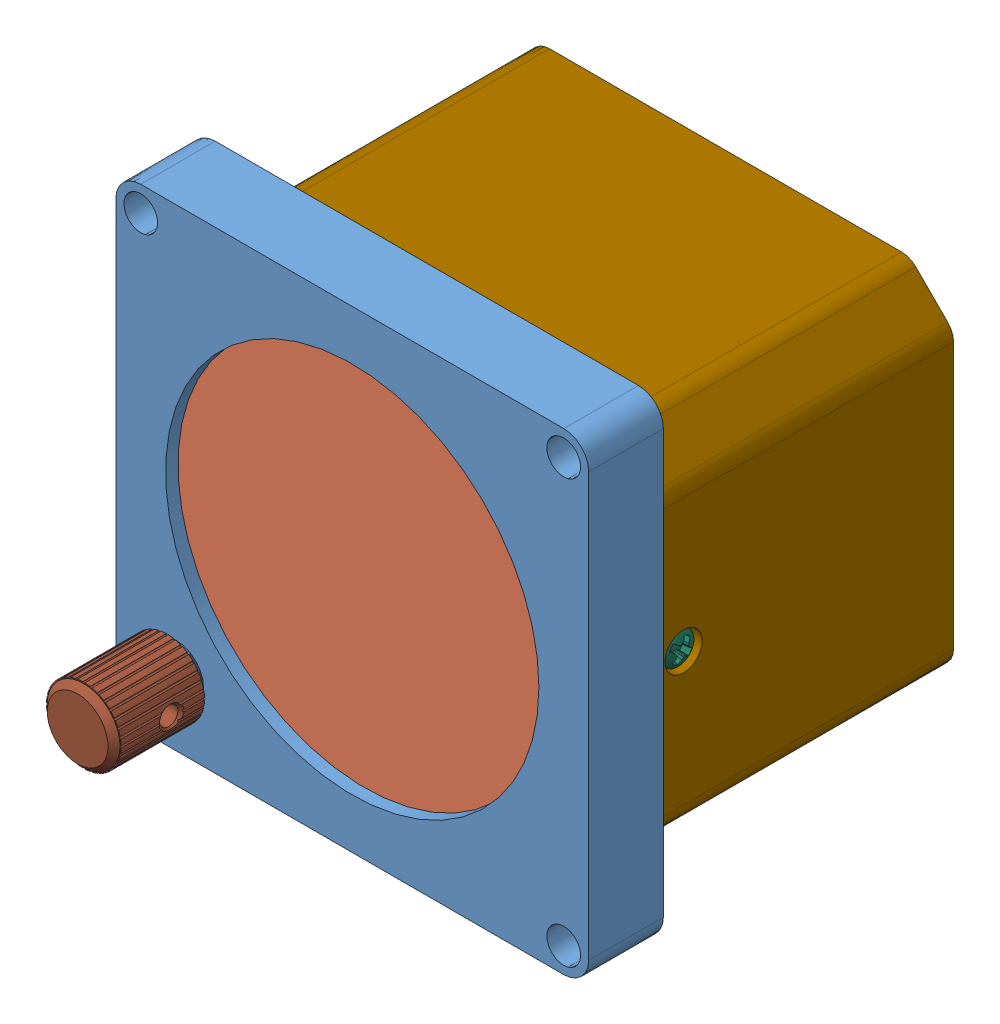
SolidWorks assembly Altimeter, configuration Default. Lengths in mm.
Overall size (60.32 60.32 60.2).
41 component instances, 17 part files, 100 mates.
Components (placement in the parent):
- Altimeter Bezel-1: Altimeter Bezel [Default] at origin size (60.32 60.32 9.53)
- Airspeed Indicator Cover Glass-1: Airspeed Indicator Cover Glass [Default] at (0 0 6.35) size (49.91 49.91 1.59)
- Airspeed Indicator Dial Face Spacer-1: Airspeed Indicator Dial Face Spacer [Default] at (0 0 1.5875) size (49.91 49.91 4.76)
- Altimeter Dial Face-1: Altimeter Dial Face [Default] at origin size (47.65 47.65 1.59)
- Altimeter Stepper Mount-1: Altimeter Stepper Mount [Default] x (-1 0 0) z (0 0 -1) size (56.37 49.44 7.31)
- Altimeter Indicator Pointer-1: Altimeter Indicator Pointer [Default] at (0 0 3.175) x (-0.470884 0.882195 0) z (0 0 1) size (3.17 35.56 0.76)
- DFR0376 DISPLAY-1: DFR0376 DISPLAY [Default] at (72.1555 -12.024 0.081) size (15.3 10.2 0.93)
- DFR0376 PCB-2: DFR0376 PCB [Default] at (-26.7105 60.1578 -5.08) x (0 1 0) z (0 0 1) size (17.8 15.5 2.87)
- DFR0376 DISPLAY-2: DFR0376 DISPLAY [Default] at (-81.2551 4.6281 0.081) x (-1 0 0) z (0 0 1) size (15.3 10.2 0.93)
- DFR0376 PCB-3: DFR0376 PCB [Default] at (19.5694 -79.5565 -5.08) x (0 -1 0) z (0 0 1) size (17.8 15.5 2.87)
- Altimeter Case-1: Altimeter Case [Default] x (-1 0 0) z (0 0 -1) size (59.24 53.76 38.1)
- PEC11R-4230F-N0024-1: PEC11R-4230F-N0024 [Default] at (-22.456 -21.4503 -10.95) x (0 1 0) z (1 0 0) size (12.5 40.2 13.9)
- Altimeter Knob-1: Altimeter Knob [Default] at (-22.456 -21.4503 9.398) x (0 -1 0) z (-1 0 0) size (9.52 11.43 9.53)
- VID29-02-1: VID29-02 [Default] at (1.5529 5.7956 -14.013) x (0.965926 -0.258819 0) z (-0.258819 -0.965926 0) size (31.7 22.35 29.3)
- MD-80PL100-1: MD-80PL100 [Default] at (0 13.4938 -34.29) x (0 0 -1) z (1 0 0) size (21.05 14 25)
- MD-80PL100-2: MD-80PL100 [Default] at (0 -2.3813 -34.29) x (0 0 -1) z (1 0 0) size (21.05 14 25)
- MD-80PL100-3: MD-80PL100 [Default] at (0 -18.2563 -34.29) x (0 0 -1) z (1 0 0) size (21.05 14 25)
- 93365A110_BRASS HEAT-SET INSERT FOR PLASTICS_2-56-2: 93365A110_BRASS HEAT-SET INSERT FOR PLASTICS_2-56 [Default] at (-27.2185 10.9575 -3.6565) x (0 0.185827 0.982583) z (0 -0.982583 0.185827) size (3.58 3.09 3.58)
- 93365A110_BRASS HEAT-SET INSERT FOR PLASTICS_2-56-6: 93365A110_BRASS HEAT-SET INSERT FOR PLASTICS_2-56 [Default] at (0 -26.2128 -3.6565) x (0.133778 0 0.991011) z (0.991011 0 -0.133778) size (3.58 3.09 3.58)
- 93365A110_BRASS HEAT-SET INSERT FOR PLASTICS_2-56-7: 93365A110_BRASS HEAT-SET INSERT FOR PLASTICS_2-56 [Default] at (27.2185 0 -3.6565) x (0 -0.124503 -0.992219) z (0 -0.992219 0.124503) size (3.58 3.09 3.58)
- 90272A077_ZINC-PLTD STL PAN HEAD PHILLIPS MACHINE SCREW_2-56 X .250-6: 90272A077_ZINC-PLTD STL PAN HEAD PHILLIPS MACHINE SCREW_2-56 X .250 [90272A077] at (21.1479 0 -3.6565) x (0 -0.551669 -0.834063) z (1 0 0) size (4.24 4.24 7.94)
- 93365A102 - INSERT, 0-80, BRASS, FOR PLASTICS-1: 93365A102 - INSERT, 0-80, BRASS, FOR PLASTICS [Default] at (14.5929 2.3015 -7.313) x (0.934347 -0.356365 0) z (0.356365 0.934347 0) size (3.58 3.01 3.58)
- 91772A064 - PHS, 0-80 x .4375, 18-8-1: 91772A064 - PHS, 0-80 x .4375, 18-8 [91772A064] at (14.5929 2.3015 -3.2005) x (0.302136 0.953265 0) z (0 0 -1) size (2.95 2.95 12.24)
- 93365A102 - INSERT, 0-80, BRASS, FOR PLASTICS-2: 93365A102 - INSERT, 0-80, BRASS, FOR PLASTICS [Default] at (-11.4871 9.2896 -7.313) x (0.979031 -0.203713 0) z (0.203713 0.979031 0) size (3.58 3.01 3.58)
- 91772A064 - PHS, 0-80 x .4375, 18-8-2: 91772A064 - PHS, 0-80 x .4375, 18-8 [91772A064] at (-11.4871 9.2896 -3.2005) x (0.147171 0.989111 0) z (0 0 -1) size (2.95 2.95 12.24)
- 93365A110_BRASS HEAT-SET INSERT FOR PLASTICS_2-56-15: 93365A110_BRASS HEAT-SET INSERT FOR PLASTICS_2-56 [Default] at (0 21.7394 -3.6565) x (-0.195009 0 -0.980801) z (0.980801 0 -0.195009) size (3.58 3.09 3.58)
- 90272A077_ZINC-PLTD STL PAN HEAD PHILLIPS MACHINE SCREW_2-56 X .250-7: 90272A077_ZINC-PLTD STL PAN HEAD PHILLIPS MACHINE SCREW_2-56 X .250 [90272A077] at (0 15.6688 -3.6565) x (0.26024 0 -0.965544) z (0 1 0) size (4.24 4.24 7.94)
- 90272A077_ZINC-PLTD STL PAN HEAD PHILLIPS MACHINE SCREW_2-56 X .250-9: 90272A077_ZINC-PLTD STL PAN HEAD PHILLIPS MACHINE SCREW_2-56 X .250 [90272A077] at (-21.1479 10.9575 -3.6565) x (0 -0.972445 -0.233133) z (-1 0 0) size (4.24 4.24 7.94)
- 90272A077_ZINC-PLTD STL PAN HEAD PHILLIPS MACHINE SCREW_2-56 X .250-11: 90272A077_ZINC-PLTD STL PAN HEAD PHILLIPS MACHINE SCREW_2-56 X .250 [90272A077] at (0 -20.1422 -3.6565) x (-0.801502 0 -0.597992) z (0 -1 0) size (4.24 4.24 7.94)
- 93365A102 - INSERT, 0-80, BRASS, FOR PLASTICS-4: 93365A102 - INSERT, 0-80, BRASS, FOR PLASTICS [Default] at (-9.5 13.4938 -34.29) x (-0.370625 0.928782 0) z (0.928782 0.370625 0) size (3.58 3.01 3.58)
- 93365A102 - INSERT, 0-80, BRASS, FOR PLASTICS-6: 93365A102 - INSERT, 0-80, BRASS, FOR PLASTICS [Default] at (9.5 13.4938 -34.29) x (-0.526276 0.850314 0) z (0.850314 0.526276 0) size (3.58 3.01 3.58)
- 93365A102 - INSERT, 0-80, BRASS, FOR PLASTICS-8: 93365A102 - INSERT, 0-80, BRASS, FOR PLASTICS [Default] at (-9.5 -2.3813 -34.29) x (-0.665936 0.746009 0) z (0.746009 0.665936 0) size (3.58 3.01 3.58)
- 93365A102 - INSERT, 0-80, BRASS, FOR PLASTICS-10: 93365A102 - INSERT, 0-80, BRASS, FOR PLASTICS [Default] at (9.5 -2.3813 -34.29) x (-0.785362 0.619036 0) z (0.619036 0.785362 0) size (3.58 3.01 3.58)
- 93365A102 - INSERT, 0-80, BRASS, FOR PLASTICS-12: 93365A102 - INSERT, 0-80, BRASS, FOR PLASTICS [Default] at (-9.5 -18.2563 -34.29) x (-0.880925 0.473255 0) z (0.473255 0.880925 0) size (3.58 3.01 3.58)
- 93365A102 - INSERT, 0-80, BRASS, FOR PLASTICS-14: 93365A102 - INSERT, 0-80, BRASS, FOR PLASTICS [Default] at (9.5 -18.2563 -34.29) x (-0.949722 0.313094 0) z (0.313094 0.949722 0) size (3.58 3.01 3.58)
- 91772A064 - PHS, 0-80 x .4375, 18-8-4: 91772A064 - PHS, 0-80 x .4375, 18-8 [91772A064] at (-9.5 13.4938 -37.4025) x (0.011516 0.999934 0) z (0 0 1) size (2.95 2.95 12.24)
- 91772A064 - PHS, 0-80 x .4375, 18-8-6: 91772A064 - PHS, 0-80 x .4375, 18-8 [91772A064] at (9.5 13.4938 -37.4025) x (-0.138746 -0.990328 0) z (0 0 1) size (2.95 2.95 12.24)
- 91772A064 - PHS, 0-80 x .4375, 18-8-8: 91772A064 - PHS, 0-80 x .4375, 18-8 [91772A064] at (-9.5 -2.3813 -37.4025) x (0.230453 0.973083 0) z (0 0 1) size (2.95 2.95 12.24)
- 91772A064 - PHS, 0-80 x .4375, 18-8-10: 91772A064 - PHS, 0-80 x .4375, 18-8 [91772A064] at (9.5 -2.3813 -37.4025) x (-0.283085 -0.959095 0) z (0 0 1) size (2.95 2.95 12.24)
- 91772A064 - PHS, 0-80 x .4375, 18-8-12: 91772A064 - PHS, 0-80 x .4375, 18-8 [91772A064] at (-9.5 -18.2563 -37.4025) x (-0.292401 -0.956296 0) z (0 0 1) size (2.95 2.95 12.24)
- 91772A064 - PHS, 0-80 x .4375, 18-8-14: 91772A064 - PHS, 0-80 x .4375, 18-8 [91772A064] at (9.5 -18.2563 -37.4025) x (0.253202 0.967413 0) z (0 0 1) size (2.95 2.95 12.24)
Mates (geometry in assembly coordinates):
- InPlace1: in place: plane of ? through (0 0 0) normal (0 0 1); moOrthogonalPlaneRef_w of ? through (0 0 0) normal (0 1 0); plane of ? through (0 0 0) normal (1 0 0); unknown of ?
- Coincident1: coincident: plane of Altimeter Bezel-1; plane of assembly
- Coincident2: coincident: plane of ? through (0 0 0) normal (0 1 0)
- Coincident3: coincident: plane of ? through (0 0 0) normal (1 0 0)
- Concentric1: concentric: cylinder of Altimeter Bezel-1 through (0 0 81.1874) axis (0 0 -1) radius 25.3365; cylinder of Airspeed Indicator Cover Glass-1 through (0 0 7.9375) axis (0 0 -1) radius 24.9555
- Coincident1: coincident: plane of Altimeter Bezel-1 through (0 0 7.9375) normal (0 0 -1); plane of Airspeed Indicator Cover Glass-1 through (0 0 7.9375) normal (0 0 1)
- Concentric2: concentric: cylinder of Altimeter Bezel-1 through (0 0 81.1874) axis (0 0 -1) radius 25.3365; cylinder of Airspeed Indicator Dial Face Spacer-1 through (0 0 6.35) axis (0 0 -1) radius 24.9555
- Coincident2: coincident: plane of Airspeed Indicator Cover Glass-1 through (0 0 6.35) normal (0 0 -1); plane of Airspeed Indicator Dial Face Spacer-1 through (0 0 6.35) normal (0 0 1)
- Concentric5: concentric: cylinder of Altimeter Bezel-1 through (0 0 81.1874) axis (0 0 -1) radius 25.3365; cylinder of Altimeter Dial Face-1 through (0 0 1.5875) axis (0 0 -1) radius 23.8252
- Parallel1: parallel: plane of Altimeter Bezel-1 through (30.1625 0 9.525) normal (1 0 0); plane of Altimeter Dial Face-1 through (0 0 0) normal (1 0 0)
- Coincident7: coincident: plane of Altimeter Dial Face-1 through (0 0 0) normal (0 0 -1); plane of Altimeter Stepper Mount-1 through (0 0 0) normal (0 0 1)
- Parallel2: parallel: plane of Altimeter Bezel-1 through (30.1625 0 9.525) normal (1 0 0); plane of Altimeter Stepper Mount-1 through (0 0 0) normal (-1 0 0)
- Distance1: distance = 1.5875 mm: plane of Altimeter Indicator Pointer-1 through (0 0 3.175) normal (0 0 -1); plane of Altimeter Dial Face-1 through (0 0 1.5875) normal (0 0 1)
- Coincident13: coincident: plane of Airspeed Indicator Dial Face Spacer-1 through (0 0 1.5875) normal (0 0 -1); plane of Altimeter Dial Face-1 through (0 0 1.5875) normal (0 0 1)
- Width4: width: plane of DFR0376 DISPLAY-1 through (-14.7246 9.8453 1.016) normal (0 -1 0); plane of DFR0376 DISPLAY-1 through (-14.7246 3.8593 1.016) normal (0 1 0); plane of Altimeter Dial Face-1 through (-8.2995 9.454 0) normal (0 -1 0); plane of Altimeter Dial Face-1 through (-8.2995 4.2506 0) normal (0 1 0)
- Width5: width: plane of DFR0376 DISPLAY-1 through (-3.4746 9.8453 1.016) normal (-1 0 0); plane of DFR0376 DISPLAY-1 through (-14.7246 9.8453 1.016) normal (1 0 0); plane of Altimeter Dial Face-1 through (-14.4706 9.454 0) normal (1 0 0); plane of Altimeter Dial Face-1 through (-3.7286 9.454 0) normal (-1 0 0)
- Coincident62: coincident: plane of Altimeter Dial Face-1 through (0 0 1.016) normal (0 0 -1); plane of DFR0376 DISPLAY-1 through (72.1555 -12.024 1.016) normal (0 0 1)
- Parallel22: parallel: plane of Altimeter Dial Face-1 through (-5.371 -16.6231 0) normal (0 1 0); plane of DFR0376 DISPLAY-2 through (7.65 -18.6982 0.851) normal (0 -1 0)
- Coincident63: coincident: plane of DFR0376 DISPLAY-1 through (72.1555 -12.024 0.081) normal (0 0 -1); plane of DFR0376 DISPLAY-2 through (-81.2551 4.6281 0.081) normal (0 0 -1)
- Width6: width: plane of DFR0376 DISPLAY-2 through (5.625 -11.2552 1.016) normal (0 -1 0); plane of DFR0376 DISPLAY-2 through (5.625 -17.2412 1.016) normal (0 1 0); plane of Altimeter Dial Face-1 through (-5.371 -16.6231 0) normal (0 1 0); plane of Altimeter Dial Face-1 through (-5.371 -11.8733 0) normal (0 -1 0)
- Width7: width: plane of DFR0376 DISPLAY-2 through (5.625 -17.2412 1.016) normal (-1 0 0); plane of DFR0376 DISPLAY-2 through (-5.625 -17.2412 1.016) normal (1 0 0); plane of Altimeter Dial Face-1 through (-5.371 -11.8733 0) normal (1 0 0); plane of Altimeter Dial Face-1 through (5.371 -11.8733 0) normal (-1 0 0)
- Coincident69: coincident: plane of Altimeter Bezel-1 through (0 0 0) normal (0 0 -1); plane of Altimeter Case-1 through (-26.9875 -26.9875 0) normal (0 0 1)
- Width8: width: plane of Altimeter Bezel-1 through (30.1625 0 9.525) normal (1 0 0); plane of Altimeter Bezel-1 through (-30.1625 0 9.525) normal (-1 0 0); plane of Altimeter Case-1 through (-29.0727 -6.8325 -38.1) normal (-1 0 0); plane of Altimeter Case-1 through (29.0727 -18.034 -38.1) normal (1 0 0)
- Parallel25: parallel: plane of Altimeter Dial Face-1 through (7.904 -6.2442 1.016) normal (0 -1 0); plane of DFR0376 PCB-3 through (9.0805 -12.9199 -2.8448) normal (0 -1 0)
- Width13: width: plane of Altimeter Stepper Mount-1 through (20.0774 -5.2318 -5.08) normal (-1 0 0); plane of Altimeter Stepper Mount-1 through (3.5614 -5.2318 -5.08) normal (1 0 0); plane of DFR0376 PCB-3 through (19.5694 -5.7398 -3.4798) normal (1 0 0); plane of DFR0376 PCB-3 through (4.0694 -5.7398 -3.4798) normal (-1 0 0)
- Width14: width: plane of DFR0376 PCB-3 through (19.5694 -5.7398 -3.4798) normal (0 1 0); plane of DFR0376 PCB-3 through (19.5694 -23.5398 -3.4798) normal (0 -1 0); plane of Altimeter Stepper Mount-1 through (3.5614 -5.2318 -5.08) normal (0 -1 0); plane of Altimeter Stepper Mount-1 through (3.5614 -24.0478 -5.08) normal (0 1 0)
- Coincident79: coincident: plane of Altimeter Stepper Mount-1 through (0 0 -5.08) normal (0 0 1); plane of DFR0376 PCB-3 through (19.5694 -79.5565 -5.08) normal (0 0 -1)
- Width15: width: plane of Altimeter Stepper Mount-1 through (-10.7025 4.6491 -5.08) normal (-1 0 0); plane of Altimeter Stepper Mount-1 through (-27.2185 -17.6276 -93.9266) normal (-1 0 0); plane of DFR0376 PCB-2 through (-11.2105 -13.6589 -3.4798) normal (1 0 0); plane of DFR0376 PCB-2 through (-26.7105 -13.6589 -3.4798) normal (-1 0 0)
- Coincident80: coincident: plane of Altimeter Stepper Mount-1 through (0 0 -5.08) normal (0 0 1); plane of DFR0376 PCB-2 through (-26.7105 60.1578 -5.08) normal (0 0 -1)
- Concentric61: concentric: cylinder of PEC11R-4230F-N0024-1 through (-22.456 -21.4503 19.05) axis (0 0 -1) radius 3; circle of assembly
- Parallel26: parallel: plane of Altimeter Bezel-1 through (-30.1625 0 9.525) normal (-1 0 0); plane of PEC11R-4230F-N0024-1 through (-15.756 -15.2003 -17.45) normal (1 0 0)
- Distance3: distance = 0.508 mm: plane of DFR0376 PCB-2 through (-26.7105 4.1411 -3.4798) normal (0 1 0); plane of Altimeter Stepper Mount-1 through (-10.7025 4.6491 -5.08) normal (0 -1 0)
- Distance5: distance = 9.525 mm: plane of PEC11R-4230F-N0024-1 through (-22.456 -21.4503 19.05) normal (0 0 1); plane of Altimeter Bezel-1 through (0 0 9.525) normal (0 0 1)
- Concentric63: concentric: cylinder of PEC11R-4230F-N0024-1 through (-22.456 -21.4503 19.05) axis (0 0 -1) radius 3; cone of Altimeter Knob-1 through (-22.456 -21.4503 22.098) axis (0 0 1)
- Parallel29: parallel: plane of PEC11R-4230F-N0024-1 through (-20.956 -24.0484 7.05) normal (1 0 0); plane of Altimeter Knob-1 through (-20.829 -18.7799 19.05) normal (-1 0 0)
- Coincident90: coincident: plane of PEC11R-4230F-N0024-1 through (-22.456 -21.4503 19.05) normal (0 0 1); plane of Altimeter Knob-1 through (-22.456 -21.4503 19.05) normal (0 0 -1)
- Parallel30: parallel: line of Altimeter Stepper Mount-1 through (34.5319 27.2185 -17.266) axis (0 0 1); plane of Altimeter Case-1 through (-26.9875 -26.9875 0) normal (0 0 1)
- Concentric67: concentric: cylinder of Altimeter Dial Face-1 through (0 0 0) axis (0 0 1) radius 0.7937; cylinder of Altimeter Indicator Pointer-1 through (0 0 3.937) axis (0 0 -1) radius 0.5
- Concentric68: concentric: cylinder of Altimeter Indicator Pointer-1 through (0 0 3.937) axis (0 0 -1) radius 0.5; cylinder of VID29-02-1 through (0 0 -7.613) axis (0 0 -1) radius 0.5
- Coincident97: coincident: plane of Altimeter Indicator Pointer-1 through (0 0 3.937) normal (0 0 1); plane of VID29-02-1 through (0 0 3.937) normal (0 0 1)
- Parallel32: parallel: plane of Altimeter Stepper Mount-1 through (-18.2716 26.2128 -93.9266) normal (0 1 0); plane of VID29-02-1
- Concentric69: concentric: cylinder of Airspeed Indicator Dial Face Spacer-1 through (0 0 6.35) axis (0 0 -1) radius 23.368; cylinder of Altimeter Stepper Mount-1 through (0 0 -75.5164) axis (0 0 1) radius 7.9375
- Angle1: planar angle = 0.261799 rad: plane of VID29-02-1 through (0.8795 20.7804 -7.613) normal (0.258819 0.965926 0); plane of Altimeter Stepper Mount-1 through (22.745 21.7394 0) normal (0 1 0)
- Concentric70: concentric: cone of Altimeter Stepper Mount-1 through (14.5929 2.3015 -7.313) axis (0 0 1); cone of 93365A102 - INSERT, 0-80, BRASS, FOR PLASTICS-1 through (14.5929 2.3015 -6.203) axis (0 0 1)
- Coincident98: coincident: plane of Altimeter Stepper Mount-1 through (14.5929 2.3015 -7.313) normal (0 0 -1); plane of 93365A102 - INSERT, 0-80, BRASS, FOR PLASTICS-1 through (12.9198 2.9396 -7.313) normal (0 0 -1)
- Concentric71: concentric: cylinder of VID29-02-1 through (14.5929 2.3015 -14.313) axis (0 0 -1) radius 0.925; cylinder of 91772A064 - PHS, 0-80 x .4375, 18-8-1 through (14.5929 2.3015 -3.2005) axis (0 0 1) radius 1.4732
- Coincident99: coincident: plane of VID29-02-1 through (1.5529 5.7956 -14.313) normal (0 0 -1); plane of 91772A064 - PHS, 0-80 x .4375, 18-8-1 through (14.5929 2.3015 -14.313) normal (0 0 1)
- Concentric72: concentric: cone of Altimeter Stepper Mount-1 through (-11.4871 9.2896 -7.313) axis (0 0 1); cone of 93365A102 - INSERT, 0-80, BRASS, FOR PLASTICS-2 through (-11.4871 9.2896 -6.203) axis (0 0 1)
- Coincident100: coincident: plane of Altimeter Stepper Mount-1 through (14.5929 2.3015 -7.313) normal (0 0 -1); plane of 93365A102 - INSERT, 0-80, BRASS, FOR PLASTICS-2 through (-13.2402 9.6544 -7.313) normal (0 0 -1)
- Concentric73: concentric: cylinder of VID29-02-1 through (-11.4871 9.2896 -14.313) axis (0 0 -1) radius 0.925; cylinder of 91772A064 - PHS, 0-80 x .4375, 18-8-2 through (-11.4871 9.2896 -3.2005) axis (0 0 1) radius 1.4732
- Coincident101: coincident: plane of VID29-02-1 through (1.5529 5.7956 -14.313) normal (0 0 -1); plane of 91772A064 - PHS, 0-80 x .4375, 18-8-2 through (-11.4871 9.2896 -14.313) normal (0 0 1)
- Concentric74: concentric: cone of Altimeter Stepper Mount-1 through (27.2185 0 -3.6565) axis (-1 0 0); cone of 93365A110_BRASS HEAT-SET INSERT FOR PLASTICS_2-56-7 through (26.1085 0 -3.6565) axis (-1 0 0)
- Coincident102: coincident: plane of Altimeter Stepper Mount-1 through (27.2185 17.266 -93.9266) normal (1 0 0); plane of 93365A110_BRASS HEAT-SET INSERT FOR PLASTICS_2-56-7 through (27.2185 0.2229 -1.8797) normal (1 0 0)
- Concentric75: concentric: cone of Altimeter Stepper Mount-1 through (-27.2185 10.9575 -3.6565) axis (1 0 0); cone of 93365A110_BRASS HEAT-SET INSERT FOR PLASTICS_2-56-2 through (-26.1085 10.9575 -3.6565) axis (1 0 0)
- Coincident103: coincident: plane of Altimeter Stepper Mount-1 through (-27.2185 -17.6276 -93.9266) normal (-1 0 0); circle of 93365A110_BRASS HEAT-SET INSERT FOR PLASTICS_2-56-2
- Concentric76: concentric: cone of Altimeter Stepper Mount-1 through (0 -26.2128 -3.6565) axis (0 1 0); cone of 93365A110_BRASS HEAT-SET INSERT FOR PLASTICS_2-56-6 through (0 -25.1028 -3.6565) axis (0 1 0)
- Coincident104: coincident: plane of Altimeter Stepper Mount-1 through (18.2716 -26.2128 -93.9266) normal (0 -1 0); circle of 93365A110_BRASS HEAT-SET INSERT FOR PLASTICS_2-56-6
- Concentric77: concentric: cone of Altimeter Stepper Mount-1 through (0 21.7394 -3.6565) axis (0 -1 0); cone of 93365A110_BRASS HEAT-SET INSERT FOR PLASTICS_2-56-15 through (0 20.6294 -3.6565) axis (0 -1 0)
- Coincident105: coincident: plane of Altimeter Stepper Mount-1 through (22.745 21.7394 0) normal (0 1 0); plane of 93365A110_BRASS HEAT-SET INSERT FOR PLASTICS_2-56-15 through (0.3492 21.7394 -1.9002) normal (0 1 0)
- Concentric78: concentric: cylinder of Altimeter Case-1 through (29.0727 0 -3.6565) axis (1 0 0) radius 2.3813; cylinder of 90272A077_ZINC-PLTD STL PAN HEAD PHILLIPS MACHINE SCREW_2-56 X .250-6 through (21.1479 0 -3.6565) axis (-1 0 0) radius 2.1209
- Coincident106: coincident: plane of Altimeter Case-1 through (27.4979 1.3526 -3.6565) normal (1 0 0); plane of 90272A077_ZINC-PLTD STL PAN HEAD PHILLIPS MACHINE SCREW_2-56 X .250-6 through (27.4979 0 -3.6565) normal (-1 0 0)
- Concentric79: concentric: cylinder of Altimeter Case-1 through (0 23.5936 -3.6565) axis (0 1 0) radius 2.3813; cylinder of 90272A077_ZINC-PLTD STL PAN HEAD PHILLIPS MACHINE SCREW_2-56 X .250-7 through (0 15.6688 -3.6565) axis (0 -1 0) radius 2.1209
- Coincident107: coincident: plane of Altimeter Case-1 through (-1.3526 22.0188 -3.6565) normal (0 1 0); plane of 90272A077_ZINC-PLTD STL PAN HEAD PHILLIPS MACHINE SCREW_2-56 X .250-7 through (0 22.0188 -3.6565) normal (0 -1 0)
- Concentric80: concentric: cylinder of Altimeter Case-1 through (-29.0727 10.9575 -3.6565) axis (-1 0 0) radius 2.3813; cylinder of 90272A077_ZINC-PLTD STL PAN HEAD PHILLIPS MACHINE SCREW_2-56 X .250-9 through (-21.1479 10.9575 -3.6565) axis (1 0 0) radius 2.1209
- Coincident108: coincident: plane of Altimeter Case-1 through (-27.4979 12.3101 -3.6565) normal (-1 0 0); plane of 90272A077_ZINC-PLTD STL PAN HEAD PHILLIPS MACHINE SCREW_2-56 X .250-9 through (-27.4979 10.9575 -3.6565) normal (1 0 0)
- Concentric81: concentric: cylinder of Altimeter Case-1 through (0 -28.067 -3.6565) axis (0 -1 0) radius 2.3813; cylinder of 90272A077_ZINC-PLTD STL PAN HEAD PHILLIPS MACHINE SCREW_2-56 X .250-11 through (0 -20.1422 -3.6565) axis (0 1 0) radius 2.1209
- Coincident109: coincident: plane of Altimeter Case-1 through (-1.3526 -26.4922 -3.6565) normal (0 -1 0); plane of 90272A077_ZINC-PLTD STL PAN HEAD PHILLIPS MACHINE SCREW_2-56 X .250-11 through (0 -26.4922 -3.6565) normal (0 1 0)
- Coincident110: coincident: plane of Altimeter Case-1 through (-26.9875 -26.9875 -34.29) normal (0 0 1); plane of MD-80PL100-1 through (0 13.4938 -34.29) normal (0 0 -1)
- Coincident111: coincident: plane of MD-80PL100-1 through (0 13.4938 -34.29) normal (1 0 0); plane of assembly through (0 0 0) normal (1 0 0)
- Coincident112: coincident: plane of Altimeter Case-1 through (-26.9875 -26.9875 -34.29) normal (0 0 1); plane of MD-80PL100-2 through (0 -2.3813 -34.29) normal (0 0 -1)
- Coincident113: coincident: plane of MD-80PL100-1 through (0 13.4938 -34.29) normal (1 0 0); plane of MD-80PL100-2 through (0 -2.3813 -34.29) normal (1 0 0)
- Distance8: distance = 2.3813 mm: plane of MD-80PL100-2 through (0 -2.3813 -34.29) normal (0 1 0); plane of assembly through (0 0 0) normal (0 1 0)
- Distance6: distance = 15.875 mm: plane of MD-80PL100-1 through (0 13.4938 -34.29) normal (0 1 0); plane of MD-80PL100-2 through (0 -2.3813 -34.29) normal (0 1 0)
- Coincident115: coincident: plane of MD-80PL100-1 through (0 13.4938 -34.29) normal (1 0 0); plane of MD-80PL100-3 through (0 -18.2563 -34.29) normal (1 0 0)
- Distance7: distance = 15.875 mm: plane of MD-80PL100-3 through (0 -18.2563 -34.29) normal (0 1 0); plane of MD-80PL100-2 through (0 -2.3813 -34.29) normal (0 1 0)
- Coincident116: coincident: plane of Altimeter Case-1 through (-26.9875 -26.9875 -34.29) normal (0 0 1); plane of MD-80PL100-3 through (0 -18.2563 -34.29) normal (0 0 -1)
- Concentric82: concentric: cone of Altimeter Case-1 through (-9.5 13.4938 -34.29) axis (0 0 -1); cone of 93365A102 - INSERT, 0-80, BRASS, FOR PLASTICS-4 through (-9.5 13.4938 -35.4) axis (0 0 -1)
- Coincident117: coincident: plane of Altimeter Case-1 through (-26.9875 -26.9875 -34.29) normal (0 0 1); plane of 93365A102 - INSERT, 0-80, BRASS, FOR PLASTICS-4 through (-8.8363 11.8306 -34.29) normal (0 0 1)
- Concentric83: concentric: cone of Altimeter Case-1 through (9.5 13.4938 -34.29) axis (0 0 -1); cone of 93365A102 - INSERT, 0-80, BRASS, FOR PLASTICS-6 through (9.5 13.4938 -35.4) axis (0 0 -1)
- Coincident118: coincident: plane of Altimeter Case-1 through (-26.9875 -26.9875 -34.29) normal (0 0 1); plane of 93365A102 - INSERT, 0-80, BRASS, FOR PLASTICS-6 through (10.4424 11.9711 -34.29) normal (0 0 1)
- Concentric84: concentric: cone of Altimeter Case-1 through (-9.5 -2.3813 -34.29) axis (0 0 -1); cone of 93365A102 - INSERT, 0-80, BRASS, FOR PLASTICS-8 through (-9.5 -2.3813 -35.4) axis (0 0 -1)
- Coincident119: coincident: plane of Altimeter Case-1 through (-26.9875 -26.9875 -34.29) normal (0 0 1); plane of 93365A102 - INSERT, 0-80, BRASS, FOR PLASTICS-8 through (-8.3075 -3.7171 -34.29) normal (0 0 1)
- Concentric85: concentric: cone of Altimeter Case-1 through (9.5 -2.3813 -34.29) axis (0 0 -1); cone of 93365A102 - INSERT, 0-80, BRASS, FOR PLASTICS-10 through (9.5 -2.3813 -35.4) axis (0 0 -1)
- Coincident120: coincident: plane of Altimeter Case-1 through (-26.9875 -26.9875 -34.29) normal (0 0 1); plane of 93365A102 - INSERT, 0-80, BRASS, FOR PLASTICS-10 through (10.9063 -3.4898 -34.29) normal (0 0 1)
- Concentric86: concentric: cone of Altimeter Case-1 through (-9.5 -18.2563 -34.29) axis (0 0 -1); cone of 93365A102 - INSERT, 0-80, BRASS, FOR PLASTICS-12 through (-9.5 -18.2563 -35.4) axis (0 0 -1)
- Coincident121: coincident: plane of Altimeter Case-1 through (-26.9875 -26.9875 -34.29) normal (0 0 1); plane of 93365A102 - INSERT, 0-80, BRASS, FOR PLASTICS-12 through (-7.9225 -19.1037 -34.29) normal (0 0 1)
- Concentric87: concentric: cone of Altimeter Case-1 through (9.5 -18.2563 -34.29) axis (0 0 -1); cone of 93365A102 - INSERT, 0-80, BRASS, FOR PLASTICS-14 through (9.5 -18.2563 -35.4) axis (0 0 -1)
- Coincident122: coincident: plane of Altimeter Case-1 through (-26.9875 -26.9875 -34.29) normal (0 0 1); plane of 93365A102 - INSERT, 0-80, BRASS, FOR PLASTICS-14 through (11.2007 -18.8169 -34.29) normal (0 0 1)
- Concentric88: concentric: cylinder of MD-80PL100-1 through (-9.5 13.4938 -21.0127) axis (0 0 -1) radius 1.05; cylinder of 91772A064 - PHS, 0-80 x .4375, 18-8-4 through (-9.5 13.4938 -37.4025) axis (0 0 -1) radius 1.4732
- Coincident123: coincident: plane of MD-80PL100-1 through (-9.5 13.4938 -26.29) normal (0 0 1); plane of 91772A064 - PHS, 0-80 x .4375, 18-8-4 through (-9.5 13.4938 -26.29) normal (0 0 -1)
- Concentric89: concentric: cylinder of MD-80PL100-1 through (9.5 13.4938 -21.0127) axis (0 0 -1) radius 1.05; cylinder of 91772A064 - PHS, 0-80 x .4375, 18-8-6 through (9.5 13.4938 -37.4025) axis (0 0 -1) radius 1.4732
- Coincident124: coincident: plane of MD-80PL100-1 through (9.5 13.4938 -26.29) normal (0 0 1); plane of 91772A064 - PHS, 0-80 x .4375, 18-8-6 through (9.5 13.4938 -26.29) normal (0 0 -1)
- Concentric90: concentric: cylinder of MD-80PL100-2 through (-9.5 -2.3813 -21.0127) axis (0 0 -1) radius 1.05; cylinder of 91772A064 - PHS, 0-80 x .4375, 18-8-8 through (-9.5 -2.3813 -37.4025) axis (0 0 -1) radius 1.4732
- Coincident125: coincident: plane of MD-80PL100-2 through (-9.5 -2.3813 -26.29) normal (0 0 1); plane of 91772A064 - PHS, 0-80 x .4375, 18-8-8 through (-9.5 -2.3813 -26.29) normal (0 0 -1)
- Concentric91: concentric: cylinder of MD-80PL100-2 through (9.5 -2.3813 -21.0127) axis (0 0 -1) radius 1.05; cylinder of 91772A064 - PHS, 0-80 x .4375, 18-8-10 through (9.5 -2.3813 -37.4025) axis (0 0 -1) radius 1.4732
- Coincident126: coincident: plane of MD-80PL100-2 through (9.5 -2.3813 -26.29) normal (0 0 1); plane of 91772A064 - PHS, 0-80 x .4375, 18-8-10 through (9.5 -2.3813 -26.29) normal (0 0 -1)
- Concentric92: concentric: cylinder of MD-80PL100-3 through (-9.5 -18.2563 -21.0127) axis (0 0 -1) radius 1.05; cylinder of 91772A064 - PHS, 0-80 x .4375, 18-8-12 through (-9.5 -18.2563 -37.4025) axis (0 0 -1) radius 1.4732
- Coincident127: coincident: plane of MD-80PL100-3 through (-9.5 -18.2563 -26.29) normal (0 0 1); plane of 91772A064 - PHS, 0-80 x .4375, 18-8-12 through (-9.5 -18.2563 -26.29) normal (0 0 -1)
- Concentric93: concentric: cylinder of MD-80PL100-3 through (9.5 -18.2563 -21.0127) axis (0 0 -1) radius 1.05; cylinder of 91772A064 - PHS, 0-80 x .4375, 18-8-14 through (9.5 -18.2563 -37.4025) axis (0 0 -1) radius 1.4732
- Coincident128: coincident: plane of MD-80PL100-3 through (9.5 -18.2563 -26.29) normal (0 0 1); plane of 91772A064 - PHS, 0-80 x .4375, 18-8-14 through (9.5 -18.2563 -26.29) normal (0 0 -1)
